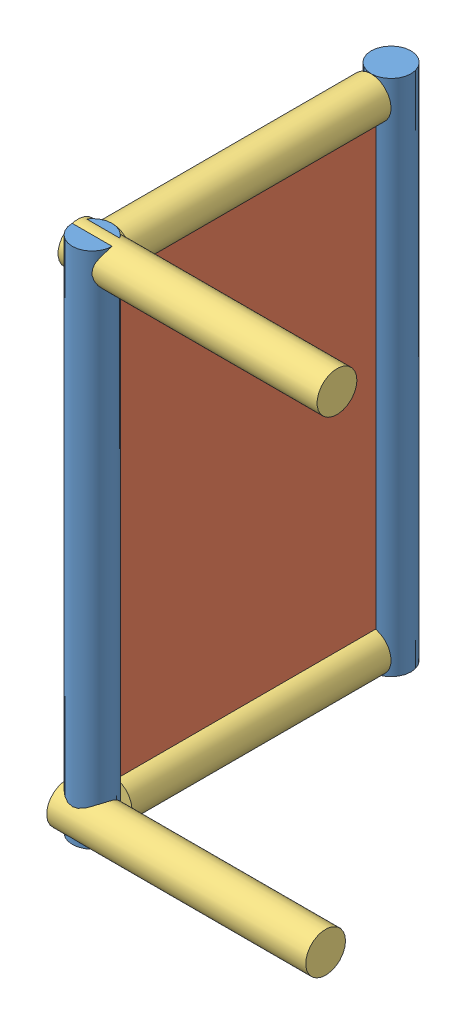
SolidWorks assembly screen_inflate, configuration Default. Lengths in mm.
Overall size (1981.2 4049.37 2671.43).
7 component instances, 3 part files, 19 mates.
Components (placement in the parent):
- screen_horiz-1: screen_horiz [Default] at (2411.4959 1330.6716 3050.2383) size (304.8 3962.4 304.8)
- screen_guts-1: screen_guts [Default] at (2449.8766 1635.4716 916.6383) x (0 1 0) z (0 0 1) size (3352.8 25.4 1981.2)
- screen_vert-1: screen_vert [Default] at (2411.4959 5140.6716 2897.8383) x (-1 0 0) z (0 -1 0) size (304.8 1981.2 304.8)
- screen_vert-2: screen_vert [Default] at (2411.4959 1483.0716 2897.8383) x (-1 0 0) z (0 -1 0) size (304.8 1981.2 304.8)
- screen_horiz-2: screen_horiz [Default] at (2411.4959 1330.6716 764.2383) size (304.8 3962.4 304.8)
- screen_vert-3: screen_vert [Default] at (2259.0959 5147.0071 3006.7534) x (0 -0.285334 0.958428) z (0 0.958428 0.285334) size (304.8 1981.2 304.8)
- screen_vert-4: screen_vert [Default] at (2259.0959 1476.736 3093.7232) x (0 -0.285334 0.958428) z (0 0.958428 0.285334) size (304.8 1981.2 304.8)
Mates (geometry in assembly coordinates):
- Parallel1: parallel: plane of screen_horiz-1 through (2411.4959 5293.0716 3050.2383) normal (0 1 0); plane of screen_guts-1 through (2424.4766 1635.4716 916.6383) normal (0 -1 0)
- Tangent2: tangent: cylinder of screen_horiz-1 through (2411.4959 5293.0716 3050.2383) axis (0 -1 0) radius 152.4; plane of screen_guts-1 through (2424.4766 1635.4716 2897.8383) normal (0 0 1)
- Coincident2: coincident: plane of screen_guts-1 through (2424.4766 1635.4716 2897.8383) normal (0 0 1); plane of screen_vert-1 through (2411.4959 5140.6716 2897.8383) normal (0 0 1)
- Tangent3: tangent: plane of screen_guts-1 through (2424.4766 4988.2716 916.6383) normal (0 1 0); cylinder of screen_vert-1 through (2411.4959 5140.6716 916.6383) axis (0 0 1) radius 152.4
- Tangent4: tangent: plane of screen_horiz-1 through (2411.4959 5293.0716 3050.2383) normal (0 1 0); cylinder of screen_vert-1 through (2411.4959 5140.6716 916.6383) axis (0 0 1) radius 152.4
- Coincident4: coincident: plane of screen_guts-1 through (2424.4766 1635.4716 916.6383) normal (0 0 -1); plane of screen_vert-2 through (2411.4959 1483.0716 916.6383) normal (0 0 -1)
- Tangent11: tangent: plane of screen_guts-1 through (2424.4766 1635.4716 916.6383) normal (0 -1 0); cylinder of screen_vert-2 through (2411.4959 1483.0716 916.6383) axis (0 0 1) radius 152.4
- Tangent12: tangent: cylinder of screen_horiz-1 through (2411.4959 5293.0716 3050.2383) axis (0 -1 0) radius 152.4; plane of screen_vert-2 through (2411.4959 1483.0716 2897.8383) normal (0 0 1)
- Coincident5: coincident: plane of screen_vert-1 through (2411.4959 5140.6716 916.6383) normal (0 0 -1); plane of screen_vert-2 through (2411.4959 1483.0716 916.6383) normal (0 0 -1)
- Parallel3: parallel: plane of screen_horiz-1 through (2411.4959 1330.6716 3050.2383) normal (0 -1 0); plane of screen_horiz-2 through (2411.4959 1330.6716 764.2383) normal (0 -1 0)
- Tangent13: tangent: plane of screen_guts-1 through (2424.4766 1635.4716 916.6383) normal (0 0 -1); cylinder of screen_horiz-2 through (2411.4959 5293.0716 764.2383) axis (0 -1 0) radius 152.4
- Coincident7: coincident: plane of screen_horiz-1 through (2411.4959 1330.6716 3050.2383) normal (0 -1 0); plane of screen_horiz-2 through (2411.4959 1330.6716 764.2383) normal (0 -1 0)
- Coincident9: coincident: point of screen_horiz-2; point of screen_vert-1
- Coincident10: coincident: point of screen_horiz-1; point of screen_vert-1
- Coincident11: coincident: point of screen_horiz-2; point of screen_vert-2
- Tangent15: tangent: cylinder of screen_horiz-1 through (2411.4959 5293.0716 3050.2383) axis (0 -1 0) radius 152.4; plane of screen_vert-4 through (2259.0959 1476.736 3093.7232) normal (-1 0 0)
- Coincident12: coincident: point of screen_horiz-1; point of screen_vert-4
- Tangent16: tangent: cylinder of screen_horiz-1 through (2411.4959 5293.0716 3050.2383) axis (0 -1 0) radius 152.4; plane of screen_vert-3 through (2259.0959 5147.0071 3006.7534) normal (-1 0 0)
- Coincident13: coincident: point of screen_horiz-1; point of screen_vert-3
